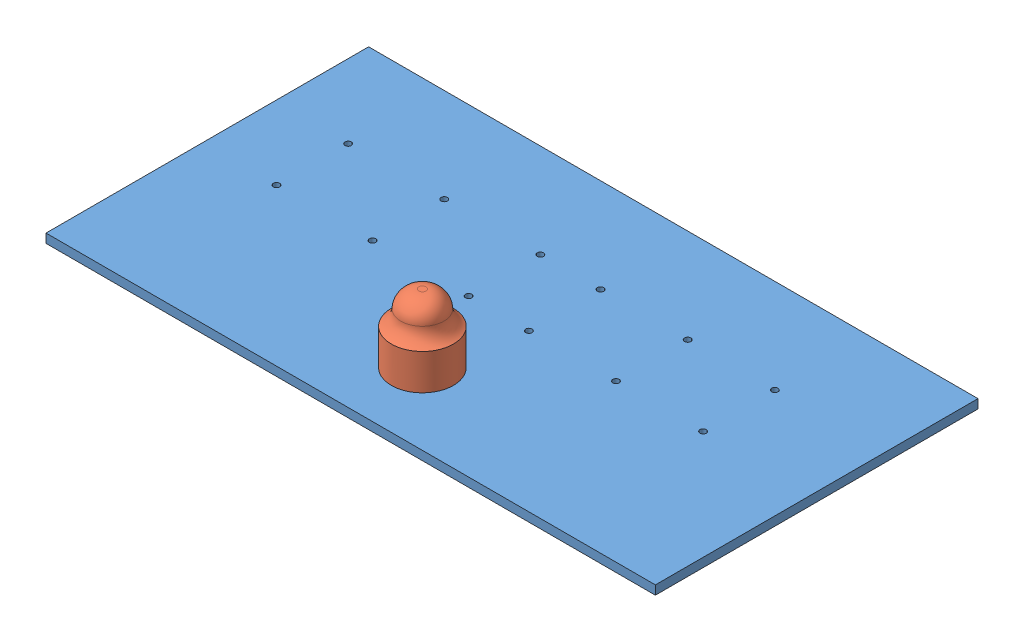
SolidWorks assembly New and Improved Signal Light board, configuration Default. Lengths in mm.
Overall size (431.8 79.12 228.6).
8 component instances, 3 part files, 20 mates.
Components (placement in the parent):
- Signal light board-1: Signal light board [Default] at origin size (431.8 6.35 228.6)
- signal light-1: signal light [Default] at (215.9 31.75 -50.8) x (-0.837169 0 -0.546944) z (-0.546944 0 0.837169) size (43.94 79.12 43.94)
- Speed Controller-2: Speed Controller [Default] at (52.2328 -8.5448 -136.4813) x (1 0 0) z (0 -1 0) size (30.12 70.11 24.39)
- Speed Controller-3: Speed Controller [Default] at (120.3149 -8.5448 -136.4813) x (1 0 0) z (0 -1 0) size (30.12 70.11 24.39)
- Speed Controller-4: Speed Controller [Default] at (188.397 -8.5448 -136.4813) x (1 0 0) z (0 -1 0) size (30.12 70.11 24.39)
- Speed Controller-5: Speed Controller [Default] at (231.079 -8.5448 -136.4813) x (1 0 0) z (0 -1 0) size (30.12 70.11 24.39)
- Speed Controller-6: Speed Controller [Default] at (292.8111 -8.5448 -136.4813) x (1 0 0) z (0 -1 0) size (30.12 70.11 24.39)
- Speed Controller-7: Speed Controller [Default] at (354.5432 -8.5448 -136.4813) x (1 0 0) z (0 -1 0) size (30.12 70.11 24.39)
Mates (geometry in assembly coordinates):
- Coincident1: coincident anti-aligned: plane of Signal light board-1 through (0 6.35 0) normal (0 1 0); plane of signal light-1 through (215.9 6.35 -50.8) normal (0 -1 0)
- Concentric1: concentric aligned: cylinder of Signal light board-1 through (215.9 0 -50.8) axis (0 1 0) radius 14.224; cylinder of signal light-1 through (215.9 -1.651 -50.8) axis (0 1 0) radius 14.224
- Coincident33: coincident anti-aligned: plane of Signal light board-1 through (0 0 0) normal (0 -1 0); plane of Speed Controller-2 through (67.1888 0 -171.4063) normal (0 1 0)
- Distance24: distance = 38.1 mm: line of Speed Controller-2 through (37.2418 -8.0412 -169.8278) axis (0 0 1); line of Signal light board-1 through (0 0 -228.6) axis (0 0 1)
- Distance25: distance = 101.6 mm: line of Speed Controller-2 through (49.3953 -0.0996 -101.6) axis (-1 0 0); line of Signal light board-1 through (0 0 0) axis (1 0 0)
- Distance27: distance = 101.6 mm: line of Speed Controller-3 through (117.4774 -0.0996 -101.6) axis (-1 0 0); line of Signal light board-1 through (0 0 0) axis (1 0 0)
- Coincident38: coincident anti-aligned: plane of Signal light board-1 through (0 0 0) normal (0 -1 0); plane of Speed Controller-4 through (203.3529 0 -171.4063) normal (0 1 0)
- Coincident39: coincident anti-aligned: plane of Signal light board-1 through (0 0 0) normal (0 -1 0); plane of Speed Controller-3 through (135.2708 0 -171.4063) normal (0 1 0)
- Distance28: distance = 101.6 mm: line of Speed Controller-4 through (185.5594 -0.0996 -101.6) axis (-1 0 0); line of Signal light board-1 through (0 0 0) axis (1 0 0)
- Distance29: distance = 38.1 mm: line of Speed Controller-4 through (173.4059 -8.0412 -169.8278) axis (0 0 1); line of Speed Controller-3 through (135.3059 -8.0412 -103.1348) axis (0 0 -1)
- Coincident42: coincident anti-aligned: plane of Signal light board-1 through (0 0 0) normal (0 -1 0); plane of Speed Controller-5 through (246.035 0 -171.4063) normal (0 1 0)
- Distance30: distance = 101.6 mm: line of Speed Controller-5 through (228.2415 -0.0996 -101.6) axis (-1 0 0); line of Signal light board-1 through (0 0 0) axis (1 0 0)
- Coincident46: coincident anti-aligned: plane of Signal light board-1 through (0 0 0) normal (0 -1 0); plane of Speed Controller-6 through (307.7671 0 -171.4063) normal (0 1 0)
- Distance32: distance = 101.6 mm: line of Speed Controller-6 through (305.6828 -0.0996 -101.6) axis (-1 0 0); line of Signal light board-1 through (0 0 0) axis (1 0 0)
- Coincident49: coincident anti-aligned: plane of Signal light board-1 through (0 0 0) normal (0 -1 0); plane of Speed Controller-7 through (369.4992 0 -171.4063) normal (0 1 0)
- Distance34: distance = 101.6 mm: line of Speed Controller-7 through (351.7057 -0.0996 -101.6) axis (-1 0 0); line of Signal light board-1 through (0 0 0) axis (1 0 0)
- Distance37: distance = 38.1 mm: line of Speed Controller-2 through (67.2239 -8.0412 -103.1348) axis (0 0 -1); line of Speed Controller-3 through (105.3239 -8.0412 -169.8278) axis (0 0 1)
- Distance39: distance = 31.75 mm: line of Speed Controller-6 through (307.8022 -8.0412 -103.1348) axis (0 0 -1); line of Speed Controller-7 through (339.5522 -8.0412 -169.8278) axis (0 0 1)
- Distance40: distance = 31.75 mm: line of Speed Controller-5 through (246.0701 -8.0412 -103.1348) axis (0 0 -1); line of Speed Controller-6 through (277.8201 -8.0412 -169.8278) axis (0 0 1)
- Distance42: distance = 12.7 mm: line of Speed Controller-5 through (216.088 -8.0412 -169.8278) axis (0 0 1); line of Speed Controller-4 through (203.388 -8.0412 -103.1348) axis (0 0 -1)
